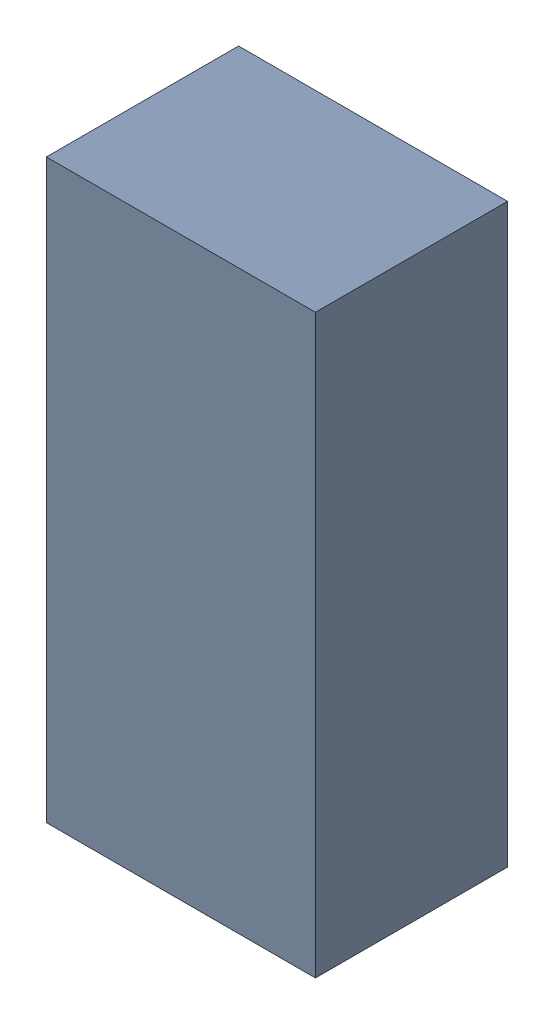
SolidWorks assembly Q2-1, configuration Default. Lengths in mm.
Overall size (1.4 3 1).
2 component instances, 1 part files, 0 mates.
Components (placement in the parent):
- 959206624-1-1: 959206624-1 [Default] at (158.496 90.17 0.1) size (1.4 3 1)
  - Extruded-41-1: Extruded-41 [Default] at origin size (1.4 3 1)
